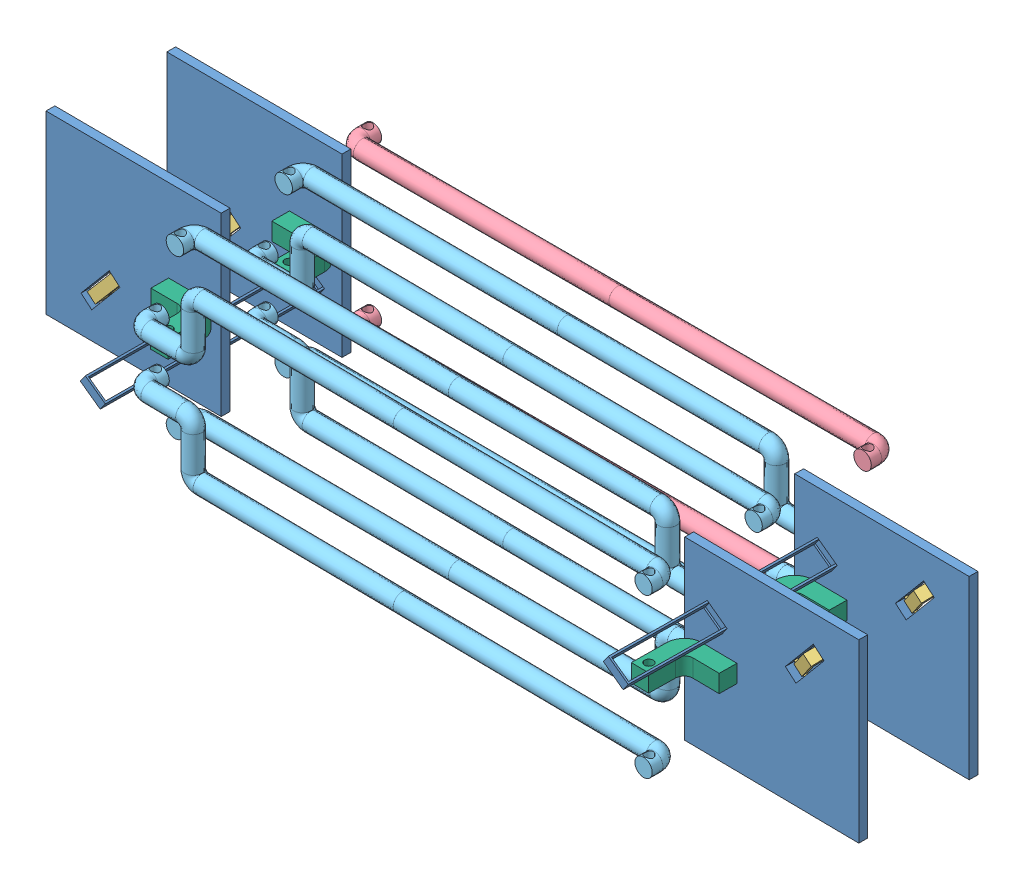
SolidWorks assembly show and tell, configuration Default. Lengths in mm.
Overall size (548.66 166.68 256.51).
26 component instances, 7 part files, 28 mates.
Components (placement in the parent):
- Copy of Copy of lock^show and tell-1: Copy of Copy of lock^show and tell [Default] at (-321.42 5.1601 281.5029) x (0.999985 0 0.005438) z (0.005438 0 -0.999985) size (100 100 67.39) (virtual)
  - Cap_base-1: Cap_base [Default] at (24.2857 56.5584 80.6695) size (100 100 66.5)
  - Cap_pin-1: Cap_pin [Default] at (24.2857 56.5584 91.6695) x (0.997914 -0.064551 0) z (0 0 1) size (80 32.64 2.5)
  - Cap_lid-1: Cap_lid [Default] at (5.7898 78.5892 82.2319) x (0.641296 -0.762398 0.086539) z (-0.765268 -0.643711 0) size (20 9.5 11)
- center_frame-1: center_frame [Default] at (-101.2196 -54.3631 121.6186) size (310 100 22)
- true_frame-2: true_frame [Default] at (-101.2938 -54.2337 150.8565) x (-0.999987 0 -0.005079) z (0.005079 0 -0.999987) size (310 100 22)
- true_frame-3: true_frame [Default] at (-101.5214 -53.9015 181.5561) x (0.999952 0 0.009749) z (0.009749 0 -0.999952) size (310 100 22)
- true_frame-4: true_frame [Default] at (-102.0224 -54.1964 243.2094) x (0.99993 0 0.011861) z (0.011861 0 -0.99993) size (310 100 22)
- true_frame-5: true_frame [Default] at (-101.7542 -54.2337 212.2017) x (-0.999985 0 -0.005438) z (0.005438 0 -0.999985) size (310 100 22)
- Part2^show and tell-1: Part2^show and tell [Default] at origin (virtual)
- lock_arm-1: lock_arm [Default] at (-276.6962 -48.3598 201.0754) x (-0.005438 0 0.999985) z (0.999985 0 0.005438) size (30 12.83 36.29)
- lock and link^show and tell-1: lock and link^show and tell [Default] at (55.4968 -143.8217 321.0097) x (0.940843 -0.068338 0.331879) z (0.331466 0.388864 -0.859601) size (122.84 124.57 128.87) (virtual)
  - Cap_lid-1: Cap_lid [Default] at (-414.7408 -13.8162 64.7088) x (0.414364 -0.492612 0.765268) z (-0.765268 -0.643711 0) size (20 9.5 11)
  - lock_arm-1: lock_arm [Default] at (-380.9537 -37.2105 88.4921) x (0.327096 -0.388864 -0.861274) z (0.942517 0.068338 0.327096) size (30 12.83 36.29)
  - Cap_pin-1: Cap_pin [Default] at (-402.9264 -27.9038 88.7171) x (0.942517 0.068338 0.327096) z (-0.327096 0.388864 0.861274) size (80 32.64 2.5)
  - Cap_base-1: Cap_base [Default] at (-399.3283 -32.1813 79.2431) x (0.942517 0.068338 0.327096) z (-0.327096 0.388864 0.861274) size (100 100 66.5)
- lock and link^show and tell-2: lock and link^show and tell [Default] at (-260.8177 35.6865 349.3657) x (-0.945661 0.068338 0.317892) z (-0.318684 -0.388864 -0.864422) size (122.84 124.57 128.87) (virtual)
  - Cap_lid-1: Cap_lid [Default] at (-414.7408 -13.8162 64.7088) x (0.414364 -0.492612 0.765268) z (-0.765268 -0.643711 0) size (20 9.5 11)
  - lock_arm-1: lock_arm [Default] at (-380.9537 -37.2105 88.4921) x (0.327096 -0.388864 -0.861274) z (0.942517 0.068338 0.327096) size (30 12.83 36.29)
  - Cap_pin-1: Cap_pin [Default] at (-402.9264 -27.9038 88.7171) x (0.942517 0.068338 0.327096) z (-0.327096 0.388864 0.861274) size (80 32.64 2.5)
  - Cap_base-1: Cap_base [Default] at (-399.3283 -32.1813 79.2431) x (0.942517 0.068338 0.327096) z (-0.327096 0.388864 0.861274) size (100 100 66.5)
- lock and link^show and tell-3: lock and link^show and tell [Default] at (-261.6728 35.3917 410.6821) x (-0.94633 0.068338 0.315894) z (-0.316857 -0.388864 -0.865093) size (122.84 124.57 128.87) (virtual)
  - Cap_lid-1: Cap_lid [Default] at (-414.7408 -13.8162 64.7088) x (0.414364 -0.492612 0.765268) z (-0.765268 -0.643711 0) size (20 9.5 11)
  - lock_arm-1: lock_arm [Default] at (-380.9537 -37.2105 88.4921) x (0.327096 -0.388864 -0.861274) z (0.942517 0.068338 0.327096) size (30 12.83 36.29)
  - Cap_pin-1: Cap_pin [Default] at (-402.9264 -27.9038 88.7171) x (0.942517 0.068338 0.327096) z (-0.327096 0.388864 0.861274) size (80 32.64 2.5)
  - Cap_base-1: Cap_base [Default] at (-399.3283 -32.1813 79.2431) x (0.942517 0.068338 0.327096) z (-0.327096 0.388864 0.861274) size (100 100 66.5)
Mates (geometry in assembly coordinates):
- Distance1: distance = 31.5 mm: point of center_frame-1; point of true_frame-2
- Distance2: distance = 60.5 mm: point of true_frame-3; point of true_frame-2
- Concentric7: concentric: cylinder of center_frame-1 through (48.7804 -104.3631 129.6186) axis (0 1 0) radius 2.5; cylinder of true_frame-2 through (48.7804 -104.2337 136.6186) axis (0 1 0) radius 2.5
- Concentric8: concentric: cylinder of true_frame-2 through (-251.3325 -104.2337 158.0946) axis (0 1 0) radius 2.5; cylinder of true_frame-3 through (-251.3681 -3.9015 165.0945) axis (0 -1 0) radius 2.5
- Distance3: distance = 60.5 mm: point of true_frame-4; point of true_frame-5
- Concentric9: concentric: cylinder of true_frame-4 through (-251.8335 -3.9015 226.3858) axis (0 -1 0) radius 2.5; cylinder of true_frame-5 through (-251.8335 -104.2337 226.3858) axis (0 1 0) radius 2.5
- Concentric10: concentric: cylinder of true_frame-3 through (48.3934 -3.9015 191.018) axis (0 -1 0) radius 2.5; cylinder of true_frame-5 through (48.3252 -104.2337 198.0177) axis (0 1 0) radius 2.5
- Distance4: distance = 60.5 mm: point of true_frame-5; point of true_frame-3
- Distance6: distance = 30 mm: point of center_frame-2; point of true_frame-7
- Distance7: distance = 60 mm: point of true_frame-8; point of true_frame-9
- Concentric13: concentric aligned: cylinder of true_frame-7 through (10.1595 -108.0336 316.8155) axis (0 1 0) radius 2.5; cylinder of center_frame-2 through (10.1595 -109.7493 316.8155) axis (0 1 0) radius 2.5
- Concentric14: concentric anti-aligned: cylinder of true_frame-8 through (-290.3869 -7.1944 407.2887) axis (0 -1 0) radius 2.5; cylinder of true_frame-9 through (-290.3869 -108.0336 407.2887) axis (0 1 0) radius 2.5
- Concentric15: concentric: cylinder of true_frame-4 through (-251.8335 -3.9015 226.3858) axis (0 -1 0) radius 2.5; cylinder of lock_arm-1 through (-251.8335 -49.2337 226.3858) axis (0 -1 0) radius 2.5
- Parallel1: parallel aligned: plane of true_frame-5 through (-251.8118 -99.2337 222.3858) normal (-0.005438 0 0.999985); plane of lock_arm-1 through (-276.8594 -58.3598 231.075) normal (-0.005438 0 0.999985)
- Distance8: distance = 45 mm: point of lock_arm-1; point of true_frame-5
- Coincident9: coincident anti-aligned: plane of Copy of Copy of lock^Assem1-1/Cap_base-1 through (-296.6959 -51.3983 200.9666) normal (-0.005438 0 0.999985); plane of lock_arm-1 through (-276.6962 -58.3598 201.0754) normal (0.005438 0 -0.999985)
- Parallel4: parallel anti-aligned: plane of Copy of Copy of lock^Assem1-1/Cap_base-1 through (-246.6695 -1.3983 196.2386) normal (0.999985 0 0.005438); plane of lock_arm-1 through (-276.6962 -58.3598 201.0754) normal (-0.999985 0 -0.005438)
- Coincident10: coincident aligned: plane of Copy of Copy of lock^Assem1-1/Cap_base-1 through (-246.6695 -1.3983 196.2386) normal (0.999985 0 0.005438); plane of lock_arm-1 through (-246.6967 -58.3598 201.2386) normal (0.999985 0 0.005438)
- Distance12: distance = 60 mm: point of lock_arm-1; line of Copy of Copy of lock^Assem1-1/Cap_base-1 through (-346.6952 -1.3983 200.6947) axis (0.999985 0 0.005438)
- Parallel8: parallel aligned: plane of true_frame-2 through (-251.3478 -9.2337 161.0945) normal (-0.005079 0 0.999987); plane of lock and link^Assem1-1/lock_arm-1 through (-276.3576 -59.1892 162.9675) normal (-0.005079 0 0.999987)
- Concentric19: concentric anti-aligned: cylinder of true_frame-2 through (-251.3325 -104.2337 158.0946) axis (0 1 0) radius 2.5; cylinder of lock and link^Assem1-1/lock_arm-1 through (-251.3325 -49.1892 158.0946) axis (0 -1 0) radius 2.5
- Distance18: distance = 45 mm: point of lock and link^Assem1-1/lock_arm-1; point of true_frame-2
- Concentric20: concentric anti-aligned: cylinder of true_frame-3 through (48.3934 -3.9015 191.018) axis (0 -1 0) radius 2.5; cylinder of lock and link^Assem1-2/lock_arm-1 through (48.3934 -58.946 191.018) axis (0 1 0) radius 2.5
- Parallel9: parallel aligned: plane of true_frame-3 through (48.3642 -8.9015 194.0179) normal (-0.009749 0 0.999952); plane of lock and link^Assem1-2/lock_arm-1 through (73.3435 -48.946 196.2615) normal (-0.009749 0 0.999952)
- Distance19: distance = 45 mm: point of lock and link^Assem1-2/lock_arm-1; point of true_frame-3
- Concentric21: concentric anti-aligned: cylinder of true_frame-4 through (47.8722 -4.1964 252.9881) axis (0 -1 0) radius 2.5; cylinder of lock and link^Assem1-3/lock_arm-1 through (47.8722 -59.2408 252.9881) axis (0 1 0) radius 2.5
- Parallel10: parallel aligned: plane of true_frame-4 through (47.8366 -9.1964 255.9878) normal (-0.011861 0 0.99993); plane of lock and link^Assem1-3/lock_arm-1 through (72.8111 -49.2408 258.2842) normal (-0.011861 0 0.99993)
- Distance20: distance = 45 mm: point of lock and link^Assem1-3/lock_arm-1; point of true_frame-4
